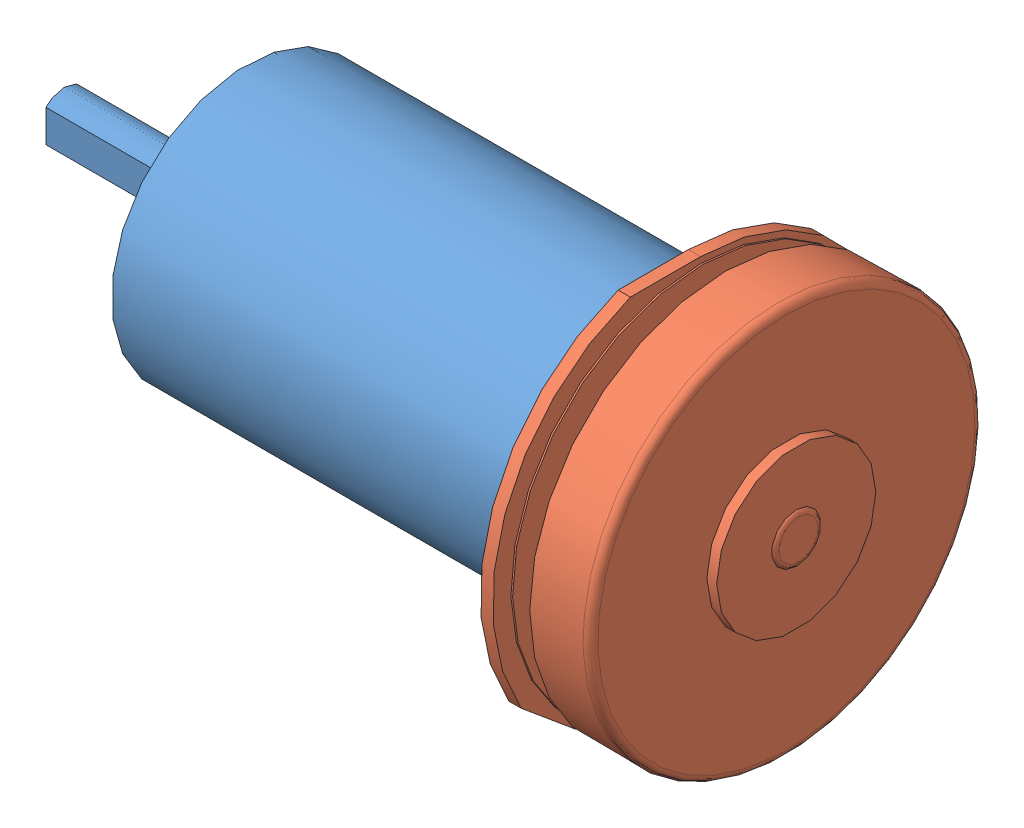
SolidWorks assembly Maxon - Combination 432941, configuration Default. Lengths in mm.
Overall size (59.95 32 33).
3 component instances, 3 part files, 9 mates.
Components (placement in the parent):
- Maxon - Gearbox 143976-1: Maxon - Gearbox 143976 [Default] at origin size (47.05 22 22)
- Maxon - Motor 339260-1: Maxon - Motor 339260 [Default] at (36.1 0 0) size (29.3 32 33)
- Maxon - Interface-1: Maxon - Interface [Default] at (36.1 0 0) x (0 0 1) z (-1 0 0) size (22 22 3.9)
Mates (geometry in assembly coordinates):
- Coincident1: coincident anti-aligned: plane of Maxon - Gearbox 143976-1 through (25.8 3.5 0) normal (1 0 0); plane of Maxon - Motor 339260-1 through (25.8 0 0) normal (-1 0 0)
- Concentric1: concentric aligned: cylinder of Maxon - Gearbox 143976-1 through (32.2 0 0) axis (-1 0 0) radius 3.5; cylinder of Maxon - Motor 339260-1 through (35.1 0 0) axis (-1 0 0) radius 5.5
- Parallel1: parallel aligned: plane of Maxon - Gearbox 143976-1 through (0 0 0) normal (0 1 0); plane of Maxon - Motor 339260-1 through (36.1 0 0) normal (0 1 0)
- Coincident3: coincident aligned: plane of Maxon - Gearbox 143976-1 through (0 0 0) normal (0 1 0); plane of assembly through (0 0 0) normal (0 1 0)
- Coincident4: coincident aligned: plane of Maxon - Gearbox 143976-1 through (0 0 0) normal (0 0 1); plane of assembly through (0 0 0) normal (0 0 1)
- Coincident5: coordinate: point of Maxon - Gearbox 143976-1; point of assembly
- Coincident7: coincident anti-aligned: plane of Maxon - Gearbox 143976-1 through (32.2 0 11) normal (1 0 0); plane of Maxon - Interface-1 through (32.2 0 0) normal (-1 0 0)
- Concentric2: concentric aligned: cylinder of Maxon - Gearbox 143976-1 through (1.6 0 0) axis (1 0 0) radius 11; cylinder of Maxon - Interface-1 through (32.2 0 0) axis (1 0 0) radius 11
- Coincident8: coincident aligned: plane of Maxon - Interface-1; plane of assembly through (0 0 0) normal (0 1 0)
